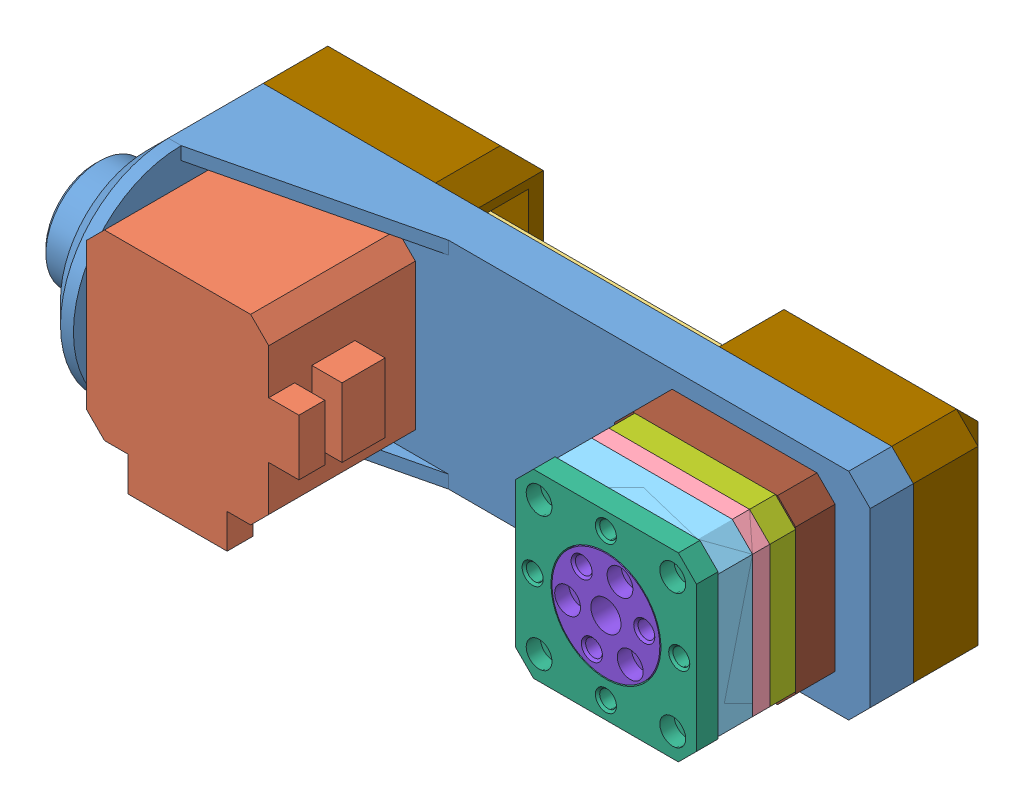
SolidWorks assembly 关节3, configuration 默认. Lengths in mm.
Overall size (167.81 54.15 67).
17 component instances, 12 part files, 31 mates.
Components (placement in the parent):
- 关节3-底座-1: 关节3-底座 [默认] at (-13.5836 -0.1513 36.2) size (167.81 50 47)
- 42步进电机-1: 42步进电机 [默认] at (48.7164 20.9987 58.2) x (0 -1 0) z (1 0 0) size (50.3 56.5 49.3)
- 同步带-270mm-1: 同步带-270mm [默认] at (125.0764 -0.1513 6.2) x (0 0 -1) z (1 0 0) size (10 25.47 122.98)
- 减速器-1: 减速器 [默认] at (104.0764 -21.1513 56.35) x (1 0 0) z (0 -1 0) size (42 23 42)
  - 主壳 v1-2-1: 主壳 v1-2 [默认] at (0 -17 0) x (1 0 0) z (0 1 0) size (42 42 4)
  - 谐波减速器-1: 谐波减速器 [默认] at (42 -5 0) x (-1 0 0) z (0 -1 0) size (42 42 10)
  - 外壳-上部-1: 外壳-上部 [默认] at (42 0 -42) x (0 0 1) z (1 0 0) size (42 5 42)
  - 主壳 v1-11-2: 主壳 v1-11 [默认] at (42 -23 -42) x (-1 0 0) z (0 1 0) size (42 42 8)
  - 输出2-1: 输出2 [默认] at (21 -5 -21) x (0.626297 0 0.779585) z (-0.779585 0 0.626297) size (28 5 28)
- 关节1-外罩-1: 关节1-外罩 [默认] at (-1.5836 24.8487 14.2) x (1 0 0) z (0 1 0) size (50 20 50)
- 挡边轴承5x9x3-1: 挡边轴承5x9x3 [默认] at (27.5664 -0.1513 -3.8) x (1 0 0) z (0 -1 0) size (10.2 3 10.2)
- 关节1-外罩-3: 关节1-外罩 [默认] at (154.2264 -25.1513 14.2) x (-1 0 0) z (0 -1 0) size (50 20 50)
- 挡边轴承5x9x3-2: 挡边轴承5x9x3 [默认] at (125.0764 -0.1513 -3.8) x (1 0 0) z (0 -1 0) size (10.2 3 10.2)
- 关节3-垫块-1: 关节3-垫块 [默认] at (125.0764 -0.1513 24.2) x (1 0 0) z (0 -1 0) size (42 9.15 42)
- 挡边轴承5x9x3-3: 挡边轴承5x9x3 [默认] at (125.0764 -0.1513 25.7) x (-0.467308 0.884095 0) z (-0.884095 -0.467308 0) size (10.2 3 10.2)
- 带轮-3: 带轮 [默认] at (125.0764 -0.1513 12.2) x (0 0 -1) z (1 0 0) size (15 27.13 27.13)
- 带轮-4: 带轮 [默认] at (27.5664 -0.1513 12.2) x (0 0 -1) z (1 0 0) size (15 27.13 27.13)
Mates (geometry in assembly coordinates):
- 平行1: parallel aligned: plane of 关节3-底座-1 through (-1.5836 24.8487 36.2) normal (0 1 0); plane of 同步带-270mm-1 through (27.5664 12.5827 11.2) normal (0 1 0)
- 重合10: coincident anti-aligned: plane of 关节3-底座-1 through (-13.5836 -0.1513 24.2) normal (0 0 1); plane of 42步进电机-1 through (48.7164 20.9987 24.2) normal (0 0 -1)
- 同心5: concentric aligned: cylinder of 关节3-底座-1 through (27.5664 -0.1513 21.2) axis (0 0 1) radius 11.5; cylinder of 42步进电机-1 through (27.5664 -0.1513 22.2) axis (0 0 1) radius 11
- 平行2: parallel aligned: plane of 关节3-底座-1 through (-1.5836 24.8487 36.2) normal (0 1 0); plane of 42步进电机-1 through (48.7164 20.9987 24.2) normal (0 1 0)
- 同心9: concentric aligned: cylinder of 关节3-底座-1 through (12.0664 15.3487 14.2) axis (0 0 1) radius 1.6; cylinder of 关节1-外罩-1 through (12.0664 15.3487 -5.8) axis (0 0 1) radius 1.6
- 同心10: concentric anti-aligned: cylinder of 关节3-底座-1 through (43.0664 15.3487 14.2) axis (0 0 1) radius 1.6; cylinder of 关节1-外罩-1 through (43.0664 15.3487 -2.5) axis (0 0 -1) radius 3.75
- 同心11: concentric anti-aligned: cylinder of 关节1-外罩-1 through (27.5664 -0.1513 9.2) axis (0 0 -1) radius 4.6; cylinder of 挡边轴承5x9x3-1 through (27.5664 -0.1513 -5.3) axis (0 0 1) radius 4.5
- 重合13: coincident anti-aligned: plane of 关节1-外罩-1 through (27.5664 -0.1513 -2.9) normal (0 0 1); plane of 挡边轴承5x9x3-1 through (27.5664 -0.1513 -2.9) normal (0 0 -1)
- 重合14: coincident anti-aligned: plane of 关节3-底座-1 through (-13.5836 -0.1513 14.2) normal (0 0 -1); plane of 关节1-外罩-1 through (-1.5836 24.8487 14.2) normal (0 0 1)
- 同心12: concentric anti-aligned: cylinder of 关节1-外罩-3 through (125.0764 -0.1513 9.2) axis (0 0 -1) radius 4.6; cylinder of 挡边轴承5x9x3-2 through (125.0764 -0.1513 -5.3) axis (0 0 1) radius 4.5
- 重合15: coincident anti-aligned: plane of 关节1-外罩-3 through (125.0764 -0.1513 -2.9) normal (0 0 1); plane of 挡边轴承5x9x3-2 through (125.0764 -0.1513 -2.9) normal (0 0 -1)
- 同心13: concentric aligned: cylinder of 关节3-底座-1 through (140.5764 15.3487 14.2) axis (0 0 1) radius 1.6; cylinder of 关节1-外罩-3 through (140.5764 15.3487 -5.8) axis (0 0 1) radius 1.6
- 同心14: concentric aligned: cylinder of 关节3-底座-1 through (109.5764 -15.6513 14.2) axis (0 0 1) radius 1.6; cylinder of 关节1-外罩-3 through (109.5764 -15.6513 -5.8) axis (0 0 1) radius 1.6
- 重合16: coincident anti-aligned: plane of 关节3-底座-1 through (-13.5836 -0.1513 14.2) normal (0 0 -1); plane of 关节1-外罩-3 through (154.2264 -25.1513 14.2) normal (0 0 1)
- 距离5: distance = 4 mm aligned: plane of 减速器-1/主壳 v1-11-1 through (119.6385 20.8487 37.35) normal (0 1 0); plane of 关节3-底座-1 through (-1.5836 24.8487 36.2) normal (0 1 0)
- 距离6: distance = 8.15 mm aligned: plane of 减速器-1/主壳 v1-11-1 through (146.0764 -5.5892 35.35) normal (1 0 0); plane of 关节3-底座-1 through (154.2264 24.8487 14.2) normal (1 0 0)
- 同心15: concentric aligned: cylinder of 关节3-垫块-1 through (125.0764 -0.1513 33.35) axis (0 0 -1) radius 2.6; cylinder of 挡边轴承5x9x3-3 through (125.0764 -0.1513 27.2) axis (0 0 -1) radius 4.5
- 重合20: coincident anti-aligned: plane of 关节3-垫块-1 through (125.0764 -0.1513 24.8) normal (0 0 -1); plane of 挡边轴承5x9x3-3 through (125.0764 -0.1513 24.8) normal (0 0 1)
- 重合21: coincident anti-aligned: plane of 关节3-底座-1 through (-13.5836 -0.1513 24.2) normal (0 0 1); plane of 关节3-垫块-1 through (125.0764 -0.1513 24.2) normal (0 0 -1)
- 同心16: concentric anti-aligned: cylinder of 关节3-底座-1 through (140.5764 15.3487 14.2) axis (0 0 1) radius 1.6; cylinder of 关节3-垫块-1 through (140.5764 15.3487 33.35) axis (0 0 -1) radius 1.6
- 同心17: concentric anti-aligned: cylinder of 关节3-底座-1 through (140.5764 -15.6513 14.2) axis (0 0 1) radius 1.6; cylinder of 关节3-垫块-1 through (140.5764 -15.6513 33.35) axis (0 0 -1) radius 1.6
- 重合22: coincident anti-aligned: plane of 减速器-1/主壳 v1-11-1 through (107.3264 -0.1513 33.35) normal (0 0 -1); plane of 关节3-垫块-1 through (125.0764 -0.1513 33.35) normal (0 0 1)
- 同心18: concentric anti-aligned: cylinder of 减速器-1/外壳-上部-1 through (109.5764 15.3487 53.05) axis (0 0 1) radius 3; cylinder of 关节3-垫块-1 through (109.5764 15.3487 33.35) axis (0 0 -1) radius 1.6
- 同心19: concentric anti-aligned: cylinder of 减速器-1/外壳-上部-1 through (140.5764 15.3487 53.05) axis (0 0 1) radius 3; cylinder of 关节3-垫块-1 through (140.5764 15.3487 33.35) axis (0 0 -1) radius 1.6
- 重合23: coincident anti-aligned: plane of 减速器-1/主壳 v1-11-2 through (142.8264 -0.1513 33.35) normal (0 0 -1); plane of 关节3-垫块-1 through (125.0764 -0.1513 33.35) normal (0 0 1)
- 同心20: concentric anti-aligned: cylinder of 同步带-270mm-1 through (125.0764 -0.1513 6.2) axis (0 0 1) radius 12.734; cylinder of 带轮-3 through (125.0764 -0.1513 14.2) axis (0 0 -1) radius 13.565
- 重合24: coincident anti-aligned: plane of 同步带-270mm-1 through (27.5664 12.5827 1.2) normal (0 0 -1); plane of 带轮-3 through (125.0764 -0.1513 1.2) normal (0 0 1)
- 同心21: concentric aligned: cylinder of 挡边轴承5x9x3-2 through (125.0764 -0.1513 -5.3) axis (0 0 1) radius 2.5; cylinder of 带轮-3 through (125.0764 -0.1513 -0.8) axis (0 0 1) radius 13.565
- 重合25: coincident anti-aligned: plane of 关节3-底座-1 through (-13.5836 -0.1513 14.2) normal (0 0 -1); plane of 带轮-3 through (125.0764 -0.1513 14.2) normal (0 0 1)
- 同心22: concentric aligned: cylinder of 挡边轴承5x9x3-1 through (27.5664 -0.1513 -5.3) axis (0 0 1) radius 2.5; cylinder of 带轮-4 through (27.5664 -0.1513 -0.8) axis (0 0 1) radius 13.565
- 重合26: coincident anti-aligned: plane of 关节3-底座-1 through (-13.5836 -0.1513 14.2) normal (0 0 -1); plane of 带轮-4 through (27.5664 -0.1513 14.2) normal (0 0 1)
